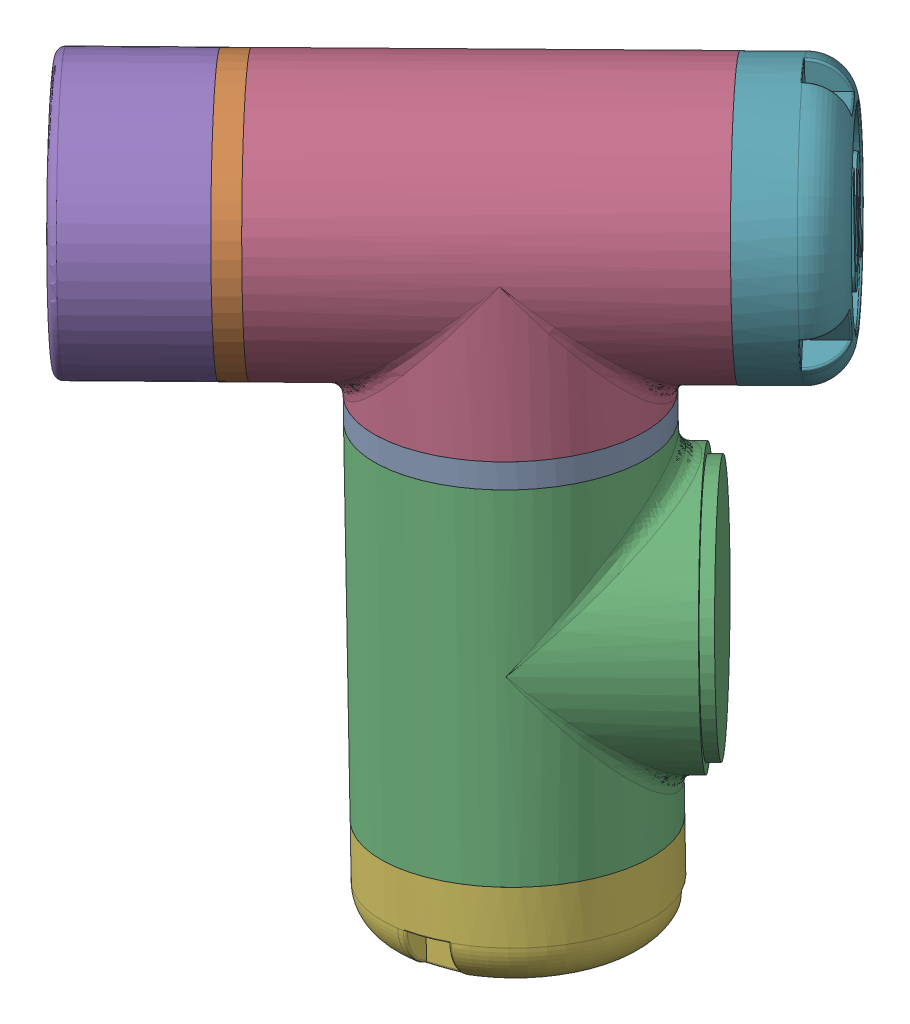
SolidWorks assembly Arm3, configuration Default. Lengths in mm.
Overall size (171.69 200.45 166.27).
7 component instances, 5 part files, 12 mates.
Components (placement in the parent):
- size 0  flange-1: size 0  flange [Default] at (-204.8868 700.691 296.12) x (0.951495 0.099422 -0.291157) z (-0.274636 -0.152099 -0.949442) size (65 6 65)
- size 0  flange-2: size 0  flange [Default] at (-246.9816 736.3905 325.4426) x (-0.112068 -0.981249 -0.156817) z (-0.665556 0.191305 -0.721413) size (65 6 65)
- size 0 shoulder 1-1: size 0 shoulder 1 [Default] at (-204.4707 697.7409 296.4722) x (0.737481 0.023412 -0.674962) z (-0.660976 -0.180197 -0.72845) size (73 88 65)
- size 0 shoulder 3-1: size 0 shoulder 3 [Default] at (-241.8164 736.5552 320.721) x (0.138681 -0.983352 0.117417) z (0.660524 0.180182 0.728863) size (73 98 65)
- Tool holder-1: Tool holder [Default] at (-249.1952 736.32 327.4662) x (0.518539 -0.65947 0.544258) z (-0.43202 -0.751363 -0.498811) size (65 35 65)
- Size 0 Cap-1: Size 0 Cap [Default] at (-192.2668 611.2059 306.8049) x (-0.650776 -0.179858 -0.737659) z (-0.746497 -0.025887 0.664885) size (65 23.19 65.09)
- Size 0 Cap-2: Size 0 Cap [Default] at (-176.8824 738.6252 261.3636) x (-0.663714 -0.156117 -0.731513) z (0.122511 -0.987458 0.099584) size (65 23.19 65.09)
Mates (geometry in assembly coordinates):
- Concentric761: concentric aligned: cylinder of size 0 shoulder 1-1 through (-204.0547 694.7908 296.8245) axis (-0.138681 0.983352 -0.117417) radius 30; cylinder of size 0  flange-1 through (-204.0547 694.7908 296.8245) axis (-0.138681 0.983352 -0.117417) radius 32.5
- Coincident23: coincident anti-aligned: plane of size 0 shoulder 1-1 through (-204.0547 694.7908 296.8245) normal (-0.138681 0.983352 -0.117417); plane of size 0  flange-1 through (-204.0547 694.7908 296.8245) normal (0.138681 -0.983352 0.117417)
- Concentric77: concentric aligned: cylinder of size 0 shoulder 3-1 through (-204.4707 697.7409 296.4722) axis (-0.138681 0.983352 -0.117417) radius 30; cylinder of size 0  flange-1 through (-204.0547 694.7908 296.8245) axis (-0.138681 0.983352 -0.117417) radius 30
- Concentric781: concentric aligned: cylinder of size 0 shoulder 3-1 through (-249.1952 736.32 327.4662) axis (0.737886 0.023523 -0.674516) radius 30; cylinder of size 0  flange-2 through (-251.4089 736.2494 329.4897) axis (0.737886 0.023523 -0.674516) radius 32.5
- Coincident25: coincident anti-aligned: plane of size 0 shoulder 3-1 through (-246.9816 736.3905 325.4426) normal (-0.737886 -0.023523 0.674516); plane of size 0  flange-2 through (-246.9816 736.3905 325.4426) normal (0.737886 0.023523 -0.674516)
- Concentric79: concentric aligned: cylinder of size 0  flange-2 through (-251.4089 736.2494 329.4897) axis (0.737886 0.023523 -0.674516) radius 30; cylinder of Tool holder-1 through (-251.4089 736.2494 329.4897) axis (0.737886 0.023523 -0.674516) radius 30
- Coincident24: coincident anti-aligned: plane of size 0 shoulder 1-1 through (-204.4707 697.7409 296.4722) normal (-0.138681 0.983352 -0.117417); plane of size 0 shoulder 3-1 through (-204.4707 697.7409 296.4722) normal (0.138681 -0.983352 0.117417)
- Concentric88: concentric anti-aligned: circle of size 0 shoulder 1-1; cylinder of Size 0 Cap-1 through (-189.0772 588.5888 309.5055) axis (-0.138681 0.983352 -0.117417) radius 32.5
- Coincident34: coincident anti-aligned: plane of size 0 shoulder 1-1 through (-192.2668 611.2059 306.8049) normal (0.138681 -0.983352 0.117417); plane of Size 0 Cap-1 through (-192.2668 611.2059 306.8049) normal (-0.138681 0.983352 -0.117417)
- Coincident26: coincident anti-aligned: plane of size 0 shoulder 3-1 through (-249.1952 736.32 327.4662) normal (-0.737886 -0.023523 0.674516); plane of Tool holder-1 through (-249.1952 736.32 327.4662) normal (0.737886 0.023523 -0.674516)
- Concentric89: concentric anti-aligned: circle of size 0 shoulder 3-1; cylinder of Size 0 Cap-2 through (-159.9111 739.1662 245.8498) axis (-0.737886 -0.023523 0.674516) radius 32.5
- Coincident35: coincident anti-aligned: plane of size 0 shoulder 3-1 through (-176.8824 738.6252 261.3636) normal (0.737886 0.023523 -0.674516); plane of Size 0 Cap-2 through (-176.8824 738.6252 261.3636) normal (-0.737886 -0.023523 0.674516)
